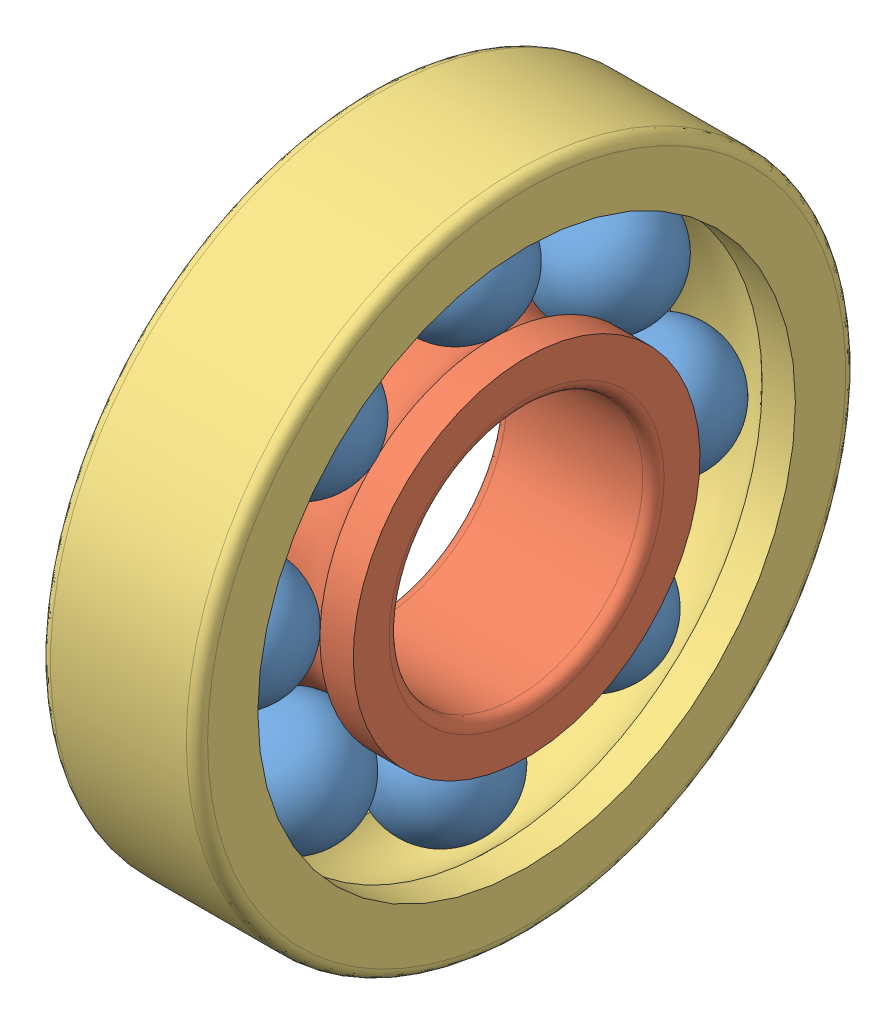
SolidWorks assembly ballbearing, configuration Default. Lengths in mm.
Overall size (37.85 130 130).
10 component instances, 3 part files, 3 mates.
Components (placement in the parent):
- ball-1: ball [Default] at (59.8745 -13.4958 -76.219) x (0.810176 -0.113683 -0.575058) z (0.226167 -0.844433 0.485573) size (24 24 24)
- inner ring-1: inner ring [Default] at (59.798 -55.6464 -74.7457) x (1 0 0) z (0 0.977494 -0.210963) size (31 68.37 68.37)
- outer ring-1: outer ring [Default] at (59.6377 -55.6464 -74.7457) size (31 130 130)
- ball-2: ball [Default] at (59.8745 -26.8832 -105.5924) x (0.810176 -0.487013 -0.326241) z (0.226167 -0.253752 0.940456) size (24 24 24)
- ball-3: ball [Default] at (59.8745 -57.1196 -116.8962) x (0.810176 -0.575058 0.113683) z (0.226167 0.485573 0.844433) size (24 24 24)
- ball-4: ball [Default] at (59.8745 -86.4931 -103.5088) x (0.810176 -0.326241 0.487013) z (0.226167 0.940456 0.253752) size (24 24 24)
- ball-5: ball [Default] at (59.8745 -97.7969 -73.2724) x (0.810176 0.113683 0.575058) z (0.226167 0.844433 -0.485573) size (24 24 24)
- ball-6: ball [Default] at (59.8745 -84.4095 -43.8989) x (0.810176 0.487013 0.326241) z (0.226167 0.253752 -0.940456) size (24 24 24)
- ball-7: ball [Default] at (59.8745 -54.1731 -32.5951) x (0.810176 0.575058 -0.113683) z (0.226167 -0.485573 -0.844433) size (24 24 24)
- ball-8: ball [Default] at (59.8745 -24.7996 -45.9825) x (0.810176 0.326241 -0.487013) z (0.226167 -0.940456 -0.253752) size (24 24 24)
Mates (geometry in assembly coordinates):
- Width1: width aligned: plane of outer ring-1 through (44.298 -2.6464 -74.7457) normal (-1 0 0); plane of outer ring-1 through (75.298 -2.6464 -74.7457) normal (1 0 0); plane of inner ring-1 through (44.298 -62.8582 -108.1615) normal (-1 0 0); plane of inner ring-1 through (75.298 -62.8582 -108.1615) normal (1 0 0)
- Coincident7: coincident aligned: axis of inner ring-1 through (88.5338 -55.6464 -74.7457) axis (-1 0 0); axis of outer ring-1 through (75.298 -55.6464 -74.7457) axis (-1 0 0)
- Tangent25: tangent: torus of inner ring-1; sphere of ball-7
